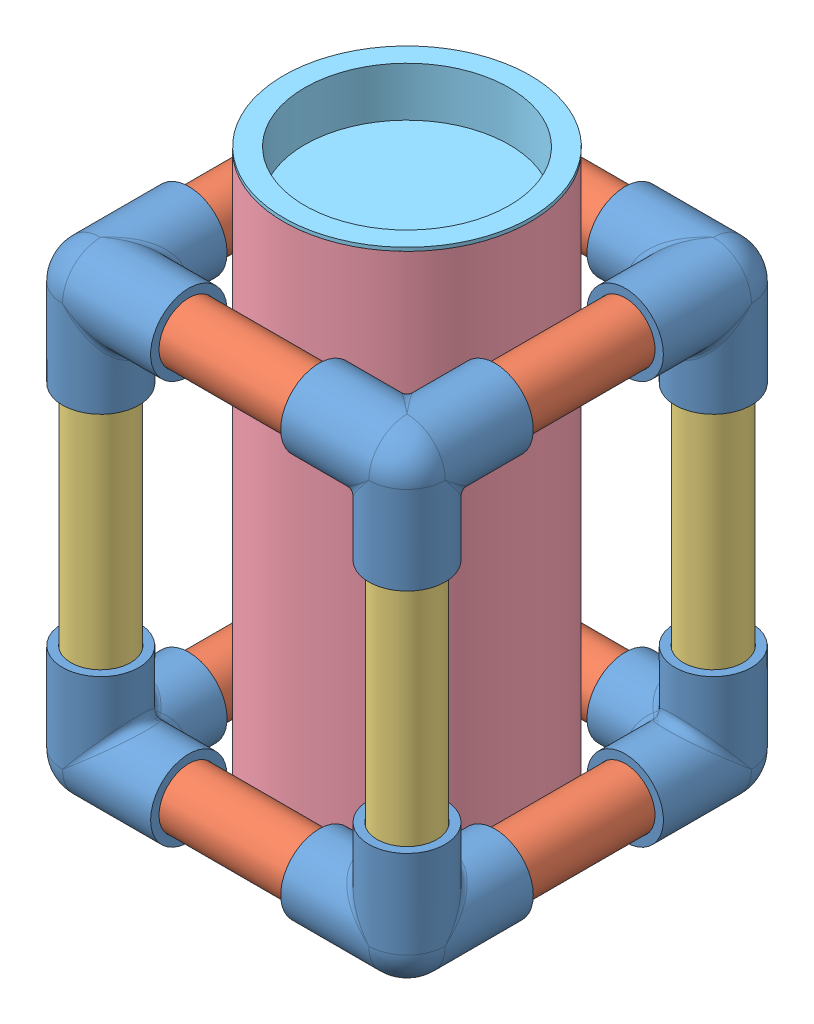
SolidWorks assembly ENVIRONMENTAL SAMPLE, configuration Default. Lengths in mm.
Overall size (137.96 201.27 139.19).
22 component instances, 5 part files, 50 mates.
Components (placement in the parent):
- 1-2 PVC SIDE OUTLET-1: 1-2 PVC SIDE OUTLET [4880K631] at (55.2 -169.7105 -55.2) size (45.53 45.53 45.53)
- 1-2 PVC SIDE OUTLET-2: 1-2 PVC SIDE OUTLET [4880K631] at (55.2 -169.7105 55.2) x (1 0 0) z (0 1 0) size (45.53 45.53 45.53)
- 1-2 PVC SIDE OUTLET-3: 1-2 PVC SIDE OUTLET [4880K631] at (-55.2 -169.7105 55.2) x (0 -1 0) z (1 0 0) size (45.53 45.53 45.53)
- 1-2 PVC SIDE OUTLET-4: 1-2 PVC SIDE OUTLET [4880K631] at (-55.2 -169.7105 -55.2) x (0 -1 0) z (0 0 1) size (45.53 45.53 45.53)
- 1-2 PVC SIDE OUTLET-5: 1-2 PVC SIDE OUTLET [4880K631] at (-55.2 -24.3105 55.2) x (-1 0 0) z (0 -1 0) size (45.53 45.53 45.53)
- 1-2 PVC SIDE OUTLET-6: 1-2 PVC SIDE OUTLET [4880K631] at (-55.2 -24.3105 -55.2) x (0 0 -1) z (0 -1 0) size (45.53 45.53 45.53)
- 1-2 PVC SIDE OUTLET-7: 1-2 PVC SIDE OUTLET [4880K631] at (55.2 -24.3105 -55.2) x (1 0 0) z (0 -1 0) size (45.53 45.53 45.53)
- 1-2 PVC SIDE OUTLET-8: 1-2 PVC SIDE OUTLET [4880K631] at (55.2 -24.3105 55.2) x (0 0 1) z (0 -1 0) size (45.53 45.53 45.53)
- 1-2 PVC PIPE 7 1-2CM-1: 1-2 PVC PIPE 7 1-2CM [48925K91] at (-55.2 -169.7105 0) size (21.34 21.34 85)
- 1-2 PVC PIPE 7 1-2CM-2: 1-2 PVC PIPE 7 1-2CM [48925K91] at (0 -169.7105 55.2) x (0 0 -1) z (1 0 0) size (21.34 21.34 85)
- 1-2 PVC PIPE 7 1-2CM-3: 1-2 PVC PIPE 7 1-2CM [48925K91] at (0 -169.7105 -55.2) x (0 0 -1) z (1 0 0) size (21.34 21.34 85)
- 1-2 PVC PIPE 7 1-2CM-4: 1-2 PVC PIPE 7 1-2CM [48925K91] at (55.2 -169.7105 0) size (21.34 21.34 85)
- 1-2 PVC PIPE 7 1-2CM-5: 1-2 PVC PIPE 7 1-2CM [48925K91] at (0 -24.3105 55.2) x (0 0 -1) z (1 0 0) size (21.34 21.34 85)
- 1-2 PVC PIPE 7 1-2CM-6: 1-2 PVC PIPE 7 1-2CM [48925K91] at (0 -24.3105 -55.2) x (0 0.632403 -0.774639) z (1 0 0) size (21.34 21.34 85)
- 1-2 PVC PIPE 7 1-2CM-7: 1-2 PVC PIPE 7 1-2CM [48925K91] at (55.2 -24.3105 0) size (21.34 21.34 85)
- 1-2 PVC PIPE 7 1-2CM-8: 1-2 PVC PIPE 7 1-2CM [48925K91] at (-55.2 -24.3105 0) size (21.34 21.34 85)
- 1-2 PVC PIPE 12CM-1: 1-2 PVC PIPE 12CM [48925K91] at (-55.2 -97.0105 55.2) x (1 0 0) z (0 -1 0) size (21.34 21.34 120)
- 1-2 PVC PIPE 12CM-2: 1-2 PVC PIPE 12CM [48925K91] at (55.2 -97.0105 55.2) x (1 0 0) z (0 -1 0) size (21.34 21.34 120)
- 1-2 PVC PIPE 12CM-3: 1-2 PVC PIPE 12CM [48925K91] at (55.2 -97.0105 -55.2) x (-0.99052 0 0.137365) z (0 -1 0) size (21.34 21.34 120)
- 1-2 PVC PIPE 12CM-4: 1-2 PVC PIPE 12CM [48925K91] at (-55.2 -97.0105 -55.2) x (1 0 0) z (0 -1 0) size (21.34 21.34 120)
- 3 PVC PIPE 20CM-1: 3 PVC PIPE 20CM [48925K97] at (0 -83.49 0) x (-1 0 0) z (0 -1 0) size (88.9 88.9 200)
- 3 KNOCKOUT TEST CAP-1: 3 KNOCKOUT TEST CAP [48925K97] at (0 -1.27 0) x (0.837169 0 0.546944) z (-0.546944 0 0.837169) size (88.9 19.05 88.9)
Mates (geometry in assembly coordinates):
- Coincident1: coincident anti-aligned: plane of 1-2 PVC SIDE OUTLET-1 through (55.2 -180.3277 -42.5) normal (0 0 1); plane of 1-2 PVC PIPE 7 1-2CM-4 through (55.2 -169.7105 -42.5) normal (0 0 -1)
- Concentric1: concentric aligned: cone of 1-2 PVC SIDE OUTLET-1 through (55.2 -169.7105 -23.45) axis (0 0 -1); cylinder of 1-2 PVC PIPE 7 1-2CM-4 through (55.2 -169.7105 42.5) axis (0 0 -1) radius 10.668
- Coincident2: coincident anti-aligned: plane of 1-2 PVC SIDE OUTLET-2 through (63.0994 -169.7105 42.5) normal (0 0 -1); plane of 1-2 PVC PIPE 7 1-2CM-4 through (55.2 -169.7105 42.5) normal (0 0 1)
- Concentric2: concentric anti-aligned: cone of 1-2 PVC SIDE OUTLET-2 through (55.2 -169.7105 42.5) axis (0 0 1); cylinder of 1-2 PVC PIPE 7 1-2CM-4 through (55.2 -169.7105 42.5) axis (0 0 -1) radius 10.668
- Coincident3: coincident anti-aligned: plane of 1-2 PVC SIDE OUTLET-1 through (42.5 -177.6099 -55.2) normal (-1 0 0); plane of 1-2 PVC PIPE 7 1-2CM-3 through (42.5 -169.7105 -55.2) normal (1 0 0)
- Concentric3: concentric anti-aligned: cone of 1-2 PVC SIDE OUTLET-1 through (23.45 -169.7105 -55.2) axis (1 0 0); cylinder of 1-2 PVC PIPE 7 1-2CM-3 through (42.5 -169.7105 -55.2) axis (-1 0 0) radius 10.668
- Coincident4: coincident anti-aligned: plane of 1-2 PVC SIDE OUTLET-4 through (-42.5 -177.6099 -55.2) normal (1 0 0); plane of 1-2 PVC PIPE 7 1-2CM-3 through (-42.5 -169.7105 -55.2) normal (-1 0 0)
- Concentric4: concentric aligned: cone of 1-2 PVC SIDE OUTLET-4 through (-42.5 -169.7105 -55.2) axis (-1 0 0); cylinder of 1-2 PVC PIPE 7 1-2CM-3 through (42.5 -169.7105 -55.2) axis (-1 0 0) radius 10.668
- Coincident6: coincident anti-aligned: plane of 1-2 PVC SIDE OUTLET-4 through (-65.8172 -169.7105 -42.5) normal (0 0 1); plane of 1-2 PVC PIPE 7 1-2CM-1 through (-55.2 -169.7105 -42.5) normal (0 0 -1)
- Concentric5: concentric aligned: cone of 1-2 PVC SIDE OUTLET-4 through (-55.2 -169.7105 -23.45) axis (0 0 -1); cylinder of 1-2 PVC PIPE 7 1-2CM-1 through (-55.2 -169.7105 42.5) axis (0 0 -1) radius 10.668
- Coincident7: coincident anti-aligned: plane of 1-2 PVC SIDE OUTLET-3 through (-55.2 -177.6099 42.5) normal (0 0 -1); plane of 1-2 PVC PIPE 7 1-2CM-1 through (-55.2 -169.7105 42.5) normal (0 0 1)
- Concentric6: concentric anti-aligned: cone of 1-2 PVC SIDE OUTLET-3 through (-55.2 -169.7105 42.5) axis (0 0 1); cylinder of 1-2 PVC PIPE 7 1-2CM-1 through (-55.2 -169.7105 42.5) axis (0 0 -1) radius 10.668
- Coincident8: coincident anti-aligned: plane of 1-2 PVC SIDE OUTLET-2 through (42.5 -169.7105 63.0994) normal (-1 0 0); plane of 1-2 PVC PIPE 7 1-2CM-2 through (42.5 -169.7105 55.2) normal (1 0 0)
- Concentric7: concentric anti-aligned: cone of 1-2 PVC SIDE OUTLET-2 through (23.45 -169.7105 55.2) axis (1 0 0); cylinder of 1-2 PVC PIPE 7 1-2CM-2 through (42.5 -169.7105 55.2) axis (-1 0 0) radius 10.668
- Concentric8: concentric aligned: cone of 1-2 PVC SIDE OUTLET-3 through (-23.45 -169.7105 55.2) axis (-1 0 0); cylinder of 1-2 PVC PIPE 7 1-2CM-2 through (42.5 -169.7105 55.2) axis (-1 0 0) radius 10.668
- Coincident9: coincident anti-aligned: plane of 1-2 PVC SIDE OUTLET-3 through (-55.2 -157.0105 63.0994) normal (0 1 0); plane of 1-2 PVC PIPE 12CM-1 through (-55.2 -157.0105 55.2) normal (0 -1 0)
- Concentric9: concentric anti-aligned: cone of 1-2 PVC SIDE OUTLET-3 through (-55.2 -137.9605 55.2) axis (0 -1 0); cylinder of 1-2 PVC PIPE 12CM-1 through (-55.2 -157.0105 55.2) axis (0 1 0) radius 10.668
- Coincident10: coincident anti-aligned: plane of 1-2 PVC SIDE OUTLET-4 through (-63.0994 -157.0105 -55.2) normal (0 1 0); plane of 1-2 PVC PIPE 12CM-4 through (-55.2 -157.0105 -55.2) normal (0 -1 0)
- Concentric10: concentric anti-aligned: cone of 1-2 PVC SIDE OUTLET-4 through (-55.2 -137.9605 -55.2) axis (0 -1 0); cylinder of 1-2 PVC PIPE 12CM-4 through (-55.2 -157.0105 -55.2) axis (0 1 0) radius 10.668
- Coincident11: coincident anti-aligned: plane of 1-2 PVC SIDE OUTLET-1 through (63.0994 -157.0105 -55.2) normal (0 1 0); plane of 1-2 PVC PIPE 12CM-3 through (55.2 -157.0105 -55.2) normal (0 -1 0)
- Concentric11: concentric anti-aligned: cone of 1-2 PVC SIDE OUTLET-1 through (55.2 -157.0105 -55.2) axis (0 -1 0); cylinder of 1-2 PVC PIPE 12CM-3 through (55.2 -157.0105 -55.2) axis (0 1 0) radius 10.668
- Coincident12: coincident anti-aligned: plane of 1-2 PVC SIDE OUTLET-2 through (55.2 -157.0105 65.8172) normal (0 1 0); plane of 1-2 PVC PIPE 12CM-2 through (55.2 -157.0105 55.2) normal (0 -1 0)
- Concentric12: concentric anti-aligned: cone of 1-2 PVC SIDE OUTLET-2 through (55.2 -137.9605 55.2) axis (0 -1 0); cylinder of 1-2 PVC PIPE 12CM-2 through (55.2 -157.0105 55.2) axis (0 1 0) radius 10.668
- Coincident13: coincident anti-aligned: plane of 1-2 PVC SIDE OUTLET-8 through (65.8172 -37.0105 55.2) normal (0 -1 0); plane of 1-2 PVC PIPE 12CM-2 through (55.2 -37.0105 55.2) normal (0 1 0)
- Concentric13: concentric aligned: cone of 1-2 PVC SIDE OUTLET-8 through (55.2 -56.0605 55.2) axis (0 1 0); cylinder of 1-2 PVC PIPE 12CM-2 through (55.2 -157.0105 55.2) axis (0 1 0) radius 10.668
- Coincident14: coincident anti-aligned: plane of 1-2 PVC SIDE OUTLET-7 through (55.2 -37.0105 -65.8172) normal (0 -1 0); plane of 1-2 PVC PIPE 12CM-3 through (55.2 -37.0105 -55.2) normal (0 1 0)
- Concentric14: concentric aligned: cone of 1-2 PVC SIDE OUTLET-7 through (55.2 -56.0605 -55.2) axis (0 1 0); cylinder of 1-2 PVC PIPE 12CM-3 through (55.2 -157.0105 -55.2) axis (0 1 0) radius 10.668
- Coincident15: coincident anti-aligned: plane of 1-2 PVC SIDE OUTLET-5 through (-55.2 -37.0105 65.8172) normal (0 -1 0); plane of 1-2 PVC PIPE 12CM-1 through (-55.2 -37.0105 55.2) normal (0 1 0)
- Concentric15: concentric aligned: cone of 1-2 PVC SIDE OUTLET-5 through (-55.2 -56.0605 55.2) axis (0 1 0); cylinder of 1-2 PVC PIPE 12CM-1 through (-55.2 -157.0105 55.2) axis (0 1 0) radius 10.668
- Coincident16: coincident anti-aligned: plane of 1-2 PVC SIDE OUTLET-6 through (-65.8172 -37.0105 -55.2) normal (0 -1 0); plane of 1-2 PVC PIPE 12CM-4 through (-55.2 -37.0105 -55.2) normal (0 1 0)
- Concentric17: concentric aligned: cylinder of 1-2 PVC SIDE OUTLET-6 through (-55.2 -10.531 -55.2) axis (0 1 0) radius 13.7795; cylinder of 1-2 PVC PIPE 12CM-4 through (-55.2 -157.0105 -55.2) axis (0 1 0) radius 10.668
- Concentric18: concentric aligned: cone of 1-2 PVC SIDE OUTLET-6 through (-42.5 -24.3105 -55.2) axis (-1 0 0); cylinder of 1-2 PVC SIDE OUTLET-7 through (23.45 -24.3105 -55.2) axis (-1 0 0) radius 13.7795
- Concentric19: concentric aligned: cone of 1-2 PVC SIDE OUTLET-7 through (55.2 -24.3105 -42.5) axis (0 0 -1); cylinder of 1-2 PVC SIDE OUTLET-8 through (55.2 -24.3105 23.45) axis (0 0 -1) radius 13.7795
- Concentric20: concentric aligned: cone of 1-2 PVC SIDE OUTLET-5 through (-23.45 -24.3105 55.2) axis (-1 0 0); cylinder of 1-2 PVC SIDE OUTLET-8 through (23.45 -24.3105 55.2) axis (-1 0 0) radius 13.7795
- Concentric21: concentric aligned: cone of 1-2 PVC SIDE OUTLET-6 through (-55.2 -24.3105 -23.45) axis (0 0 -1); cylinder of 1-2 PVC PIPE 7 1-2CM-8 through (-55.2 -24.3105 42.5) axis (0 0 -1) radius 10.668
- Concentric22: concentric aligned: cone of 1-2 PVC SIDE OUTLET-7 through (55.2 -24.3105 -42.5) axis (0 0 -1); cylinder of 1-2 PVC PIPE 7 1-2CM-7 through (55.2 -24.3105 42.5) axis (0 0 -1) radius 10.668
- Coincident18: coincident anti-aligned: plane of 1-2 PVC SIDE OUTLET-8 through (63.0994 -24.3105 42.5) normal (0 0 -1); plane of 1-2 PVC PIPE 7 1-2CM-7 through (55.2 -24.3105 42.5) normal (0 0 1)
- Coincident19: coincident anti-aligned: plane of 1-2 PVC SIDE OUTLET-5 through (-63.0994 -24.3105 42.5) normal (0 0 -1); plane of 1-2 PVC PIPE 7 1-2CM-8 through (-55.2 -24.3105 42.5) normal (0 0 1)
- Concentric23: concentric aligned: cone of 1-2 PVC SIDE OUTLET-6 through (-42.5 -24.3105 -55.2) axis (-1 0 0); cylinder of 1-2 PVC PIPE 7 1-2CM-6 through (42.5 -24.3105 -55.2) axis (-1 0 0) radius 10.668
- Concentric24: concentric aligned: cone of 1-2 PVC SIDE OUTLET-5 through (-23.45 -24.3105 55.2) axis (-1 0 0); cylinder of 1-2 PVC PIPE 7 1-2CM-5 through (42.5 -24.3105 55.2) axis (-1 0 0) radius 10.668
- Coincident20: coincident anti-aligned: plane of 1-2 PVC SIDE OUTLET-8 through (42.5 -24.3105 63.0994) normal (-1 0 0); plane of 1-2 PVC PIPE 7 1-2CM-5 through (42.5 -24.3105 55.2) normal (1 0 0)
- Coincident21: coincident anti-aligned: plane of 1-2 PVC SIDE OUTLET-7 through (42.5 -24.3105 -63.0994) normal (-1 0 0); plane of 1-2 PVC PIPE 7 1-2CM-6 through (42.5 -24.3105 -55.2) normal (1 0 0)
- Coincident22: coincident anti-aligned: plane of 3 PVC PIPE 20CM-1 through (0 16.51 0) normal (0 1 0); plane of 3 KNOCKOUT TEST CAP-1 through (31.8961 16.51 20.8386) normal (0 -1 0)
- Concentric25: concentric aligned: cylinder of 3 PVC PIPE 20CM-1 through (0 -183.49 0) axis (0 1 0) radius 38.9636; cylinder of 3 KNOCKOUT TEST CAP-1 through (0 17.78 0) axis (0 1 0) radius 38.1
- Coincident23: coincident aligned: plane of 3 KNOCKOUT TEST CAP-1 through (0 0 0) normal (0 1 0); plane of assembly through (0 0 0) normal (0 1 0)
- Coincident27: coincident aligned: plane of 1-2 PVC PIPE 7 1-2CM-2 through (0 -169.7105 55.2) normal (1 0 0); plane of assembly through (0 0 0) normal (1 0 0)
- Coincident28: coincident aligned: plane of 1-2 PVC PIPE 7 1-2CM-1 through (-55.2 -169.7105 0) normal (0 0 1); plane of assembly through (0 0 0) normal (0 0 1)
- Coincident29: coincident anti-aligned: plane of 3 PVC PIPE 20CM-1; plane of assembly through (0 0 0) normal (0 0 1)
- Coincident30: coincident anti-aligned: plane of 3 PVC PIPE 20CM-1; plane of assembly through (0 0 0) normal (1 0 0)
- Tangent4: tangent aligned: cylinder of 1-2 PVC SIDE OUTLET-4 through (-55.2 -169.7105 -68.9795) axis (0 0 -1) radius 13.7795; plane of 3 PVC PIPE 20CM-1 through (0 -183.49 0) normal (0 -1 0)
